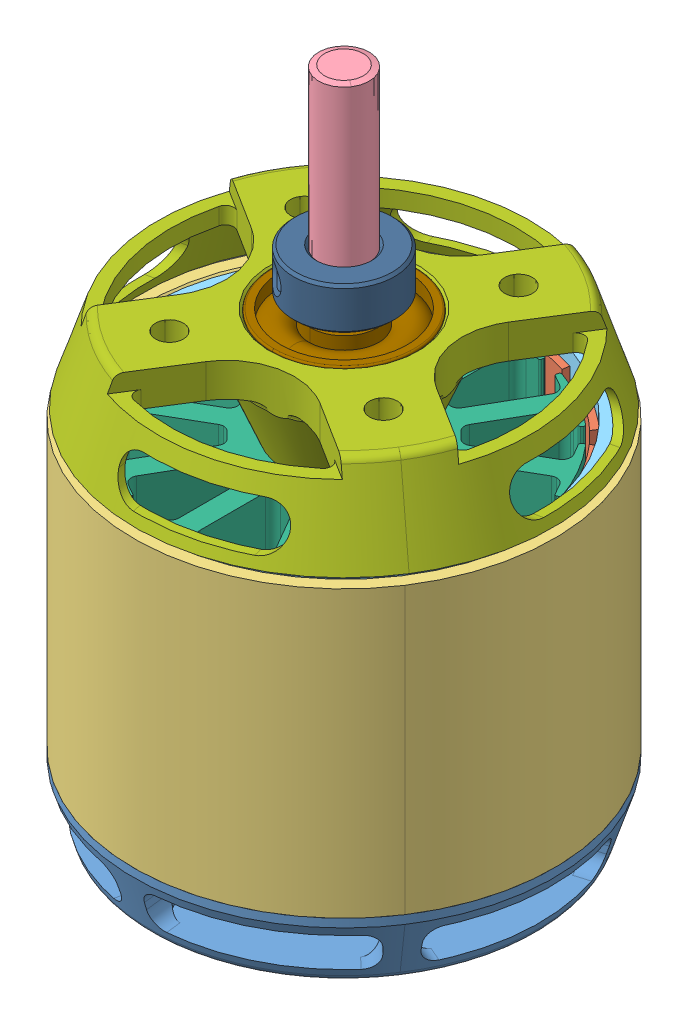
SolidWorks assembly Tempest-4130-Motor.STEP, configuration Default. Lengths in mm.
Overall size (68.93 80 68.93).
25 component instances, 10 part files, 0 mates.
Components (placement in the parent):
- 4130+_+++T+_.STEP-1: 4130+_+++T+_.STEP [Default] at (-20.8858 -13.9925 57.3737) x (0.837169 0 0.546944) z (0.546944 0 -0.837169) size (49.8 80 49.8)
  - 41-_--__+_.STEP-1: 41-_--__+_.STEP [Default] at (0.1731 5.2402 35.2) size (49.8 16.51 49.8)
  - 4130_+__.STEP-1: 4130_+__.STEP [Default] at (0.1731 -21.7598 35.2) x (-1 0 0) z (0 -1 0) size (7.2 2.92 30)
  - 4130-G+_.STEP-1: 4130-G+_.STEP [Default] at (0.1731 -21.6598 35.2) x (1 0 0) z (0 -1 0) size (49.8 49.8 33.8)
  - 4130+_+_.STEP-1: 4130+_+_.STEP [Default] at (0.1731 5.2402 35.2) x (0 1 0) z (-1 0 0) size (80 5.99 5.99)
  - 4130_+__.STEP-2: 4130_+__.STEP [Default] at (0.1731 -21.7598 35.2) x (-0.900969 0 0.433884) z (0 -1 0) size (7.2 2.92 30)
  - 4130_+__.STEP-3: 4130_+__.STEP [Default] at (0.1731 -21.7598 35.2) x (-0.62349 0 0.781831) z (0 -1 0) size (7.2 2.92 30)
  - 4130_+__.STEP-4: 4130_+__.STEP [Default] at (0.1731 -21.7598 35.2) x (-0.222521 0 0.974928) z (0 -1 0) size (7.2 2.92 30)
  - 4130_+__.STEP-5: 4130_+__.STEP [Default] at (0.1731 -21.7598 35.2) x (0.222521 0 0.974928) z (0 -1 0) size (7.2 2.92 30)
  - 4130_+__.STEP-6: 4130_+__.STEP [Default] at (0.1731 -21.7598 35.2) x (0.62349 0 0.781831) z (0 -1 0) size (7.2 2.92 30)
  - 4130_+__.STEP-7: 4130_+__.STEP [Default] at (0.1731 -21.7598 35.2) x (0.900969 0 0.433884) z (0 -1 0) size (7.2 2.92 30)
  - 4130_+__.STEP-8: 4130_+__.STEP [Default] at (0.1731 -21.7598 35.2) x (1 0 0) z (0 -1 0) size (7.2 2.92 30)
  - 4130_+__.STEP-9: 4130_+__.STEP [Default] at (0.1731 -21.7598 35.2) x (0.900969 0 -0.433884) z (0 -1 0) size (7.2 2.92 30)
  - 4130_+__.STEP-10: 4130_+__.STEP [Default] at (0.1731 -21.7598 35.2) x (0.62349 0 -0.781831) z (0 -1 0) size (7.2 2.92 30)
  - 4130_+__.STEP-11: 4130_+__.STEP [Default] at (0.1731 -21.7598 35.2) x (0.222521 0 -0.974928) z (0 -1 0) size (7.2 2.92 30)
  - 4130_+__.STEP-12: 4130_+__.STEP [Default] at (0.1731 -21.7598 35.2) x (-0.222521 0 -0.974928) z (0 -1 0) size (7.2 2.92 30)
  - 4130_+__.STEP-13: 4130_+__.STEP [Default] at (0.1731 -21.7598 35.2) x (-0.62349 0 -0.781831) z (0 -1 0) size (7.2 2.92 30)
  - 4130_+__.STEP-14: 4130_+__.STEP [Default] at (0.1731 -21.7598 35.2) x (-0.900969 0 -0.433884) z (0 -1 0) size (7.2 2.92 30)
  - XTO-41 _+___+.STEP-1: XTO-41 _+___+.STEP [Default] at (0.1731 -50.2598 35.2) x (1 0 0) z (0 0 -1) size (46.4 4.7 46.4)
- 4130__++__-+.STEP-1: 4130__++__-+.STEP [Default] at (-1.4885 -2.2327 28) size (40.6 30 40.6)
- 4130_=+_.STEP-1: 4130_=+_.STEP [Default] at (-1.4885 35.7673 28) x (0 -1 0) z (0.845805 0 0.533492) size (45.51 49.4 49.4)
- +__-MR126-ZZ.STEP-1: +__-MR126-ZZ.STEP [Default] at (-1.4885 0.7673 28) x (0 -1 0) z (0 0 1) size (4 12 12)
- +__-606-ZZ.STEP-1: +__-606-ZZ.STEP [Default] at (-1.4885 29.7673 28) x (0 1 0) z (0 0 1) size (6 17 17)
- 6.0__+_++.STEP-1: 6.0__+_++.STEP [Default] at (-1.4885 37.3173 28) x (0.837169 0 0.546944) z (-0.546944 0 0.837169) size (12 5 12)
- +__-MR126-ZZ.STEP-2: +__-MR126-ZZ.STEP [Default] at (-1.4885 -3.2327 28) x (0 -1 0) z (0 0 1) size (4 12 12)
